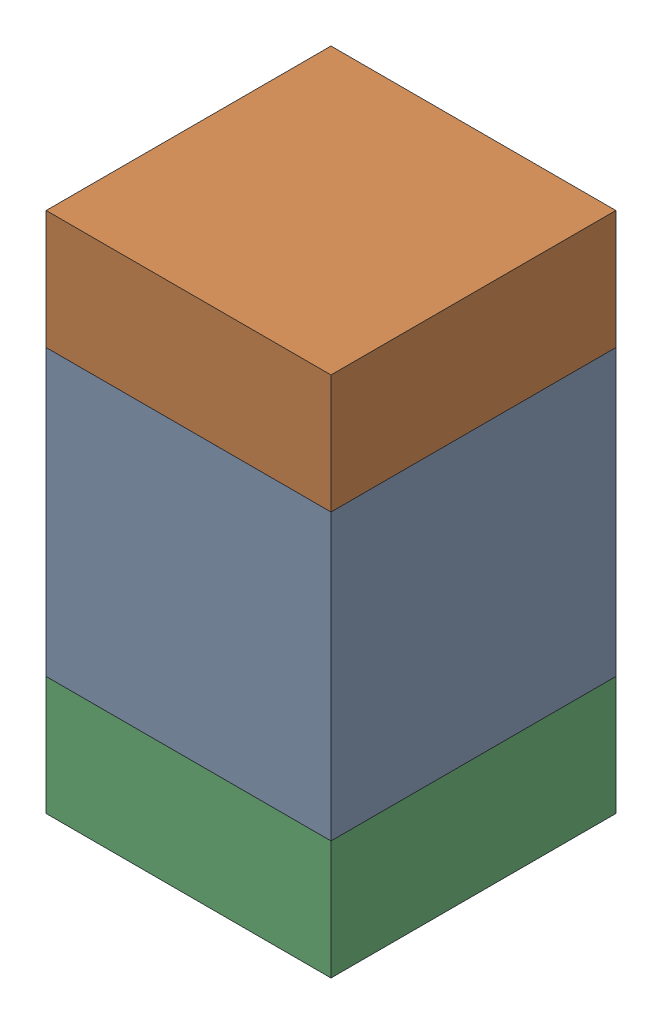
SolidWorks assembly C116_2PCB, configuration Default. Lengths in mm.
Overall size (0.6 1.1 0.6).
6 component instances, 2 part files, 0 mates.
Components (placement in the parent):
- 761606048-1: 761606048 [Default] at (114.7 89.8 0) size (0.6 0.6 0.6)
  - Extruded_9-1: Extruded_9 [Default] at origin size (0.6 0.6 0.6)
- 854785296-1: 854785296 [Default] at (114.7 90.225 0) size (0.6 0.25 0.6)
  - Extruded_10-1: Extruded_10 [Default] at origin size (0.6 0.25 0.6)
- 854785296-2: 854785296 [Default] at (114.7 89.375 0) size (0.6 0.25 0.6)
  - Extruded_10-1: Extruded_10 [Default] at origin size (0.6 0.25 0.6)
